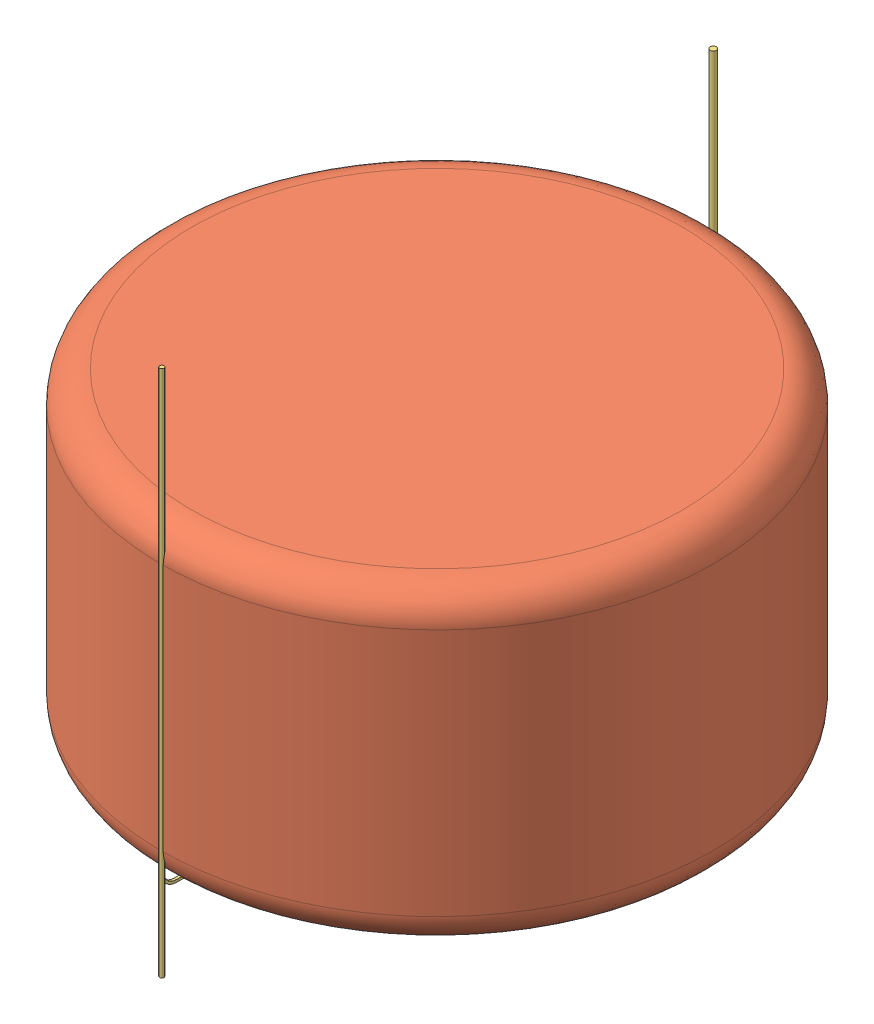
SolidWorks assembly InnerUnit, configuration 默认. Lengths in mm.
Overall size (125.56 85 125.56).
3 component instances, 3 part files, 5 mates.
Components (placement in the parent):
- BEGeDet-1: BEGeDet [默认] at (2.9686 -23.0613 80) size (80 40 80)
- InnerShell-IV-1: InnerShell-IV [默认] at (2.9686 -23.1113 80) x (0.656103 0 0.754671) z (-0.754671 0 0.656103) size (89 50 89)
- Electronics-1: Electronics [默认] at (2.9686 -48.2113 80) x (-1 0 0) z (0 0 -1) size (21.21 85 89.7)
Mates (geometry in assembly coordinates):
- 重合1: coincident anti-aligned: plane of BEGeDet-1 through (2.9686 -3.0613 80) normal (0 1 0); plane of InnerShell-IV-1 through (2.9686 -3.0613 80) normal (0 -1 0)
- 同心1: concentric aligned: circle of BEGeDet-1; circle of InnerShell-IV-1
- 同心14: concentric anti-aligned: circle of BEGeDet-1; circle of Electronics-1
- 重合10: coincident anti-aligned: plane of InnerShell-IV-1 through (2.9686 -48.1113 80) normal (0 -1 0); plane of Electronics-1 through (2.9686 -48.1113 60.201) normal (0 1 0)
- 垂直1: perpendicular: line of BEGeDet-1 through (2.9686 -43.0613 80) axis (1 0 0); line of Electronics-1 through (3.1686 -48.2113 122.2) axis (0 0 -1)
